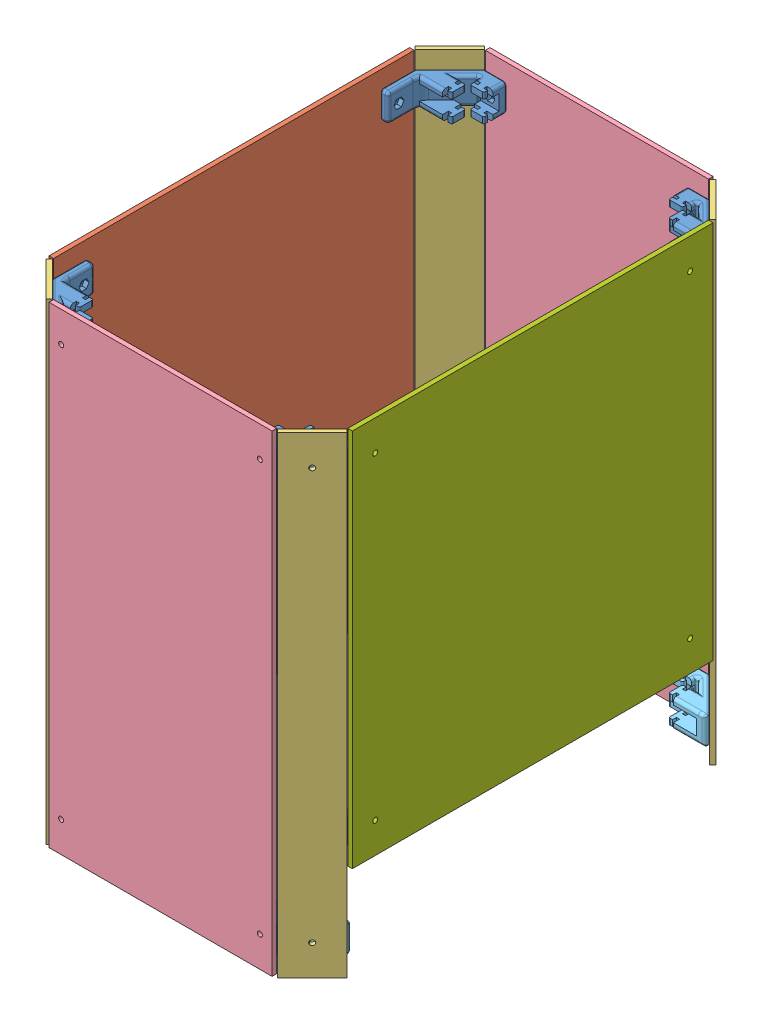
SolidWorks assembly Assemblage_plexi_exerieur, configuration Défaut. Lengths in mm.
Overall size (198.5 309 288.5).
18 component instances, 7 part files, 39 mates.
Components (placement in the parent):
- support_plexi_vis_3mm_angle_1-2: support_plexi_vis_3mm_angle_1 [Défaut] at (149.18 -29 24.6282) x (1 0 0) z (0 0 1) size (37.25 18.23 45.35)
- support_plexi_vis_3mm_angle_1-3: support_plexi_vis_3mm_angle_1 [Défaut] at (49.3175 -298 -307.1257) x (-1 0 0) z (0 0 -1) size (37.25 18.23 45.35)
- support_plexi_vis_3mm_angle_1-4: support_plexi_vis_3mm_angle_1 [Défaut] at (149.18 -11 -307.1257) x (1 0 0) z (0 0 -1) size (37.25 18.23 45.35)
- support_plexi_vis_3mm_angle_1-5: support_plexi_vis_3mm_angle_1 [Défaut] at (49.3175 -280 24.6282) x (-1 0 0) z (0 0 1) size (37.25 18.23 45.35)
- support_plexi_vis_3mm_angle_1-6: support_plexi_vis_3mm_angle_1 [Défaut] at (49.3175 -29 -307.1257) x (-1 0 0) z (0 0 -1) size (37.25 18.23 45.35)
- support_plexi_vis_3mm_angle_1-8: support_plexi_vis_3mm_angle_1 [Défaut] at (49.3175 -11 24.6282) x (-1 0 0) z (0 0 1) size (37.25 18.23 45.35)
- face arrière robot 1-1: face arrière robot 1 [Défaut] at (3 -309 -259.2487) x (0 0 1) z (-1 0 0) size (236 309 3)
- face angles-1: face angles [Défaut] at (0.9142 -309 -261.9558) x (0.707107 0 -0.707107) z (0.707107 0 0.707107) size (32 309 3)
- face angles-3: face angles [Défaut] at (23.5416 -309 2.0858) x (-0.707107 0 -0.707107) z (0.707107 0 -0.707107) size (32 309 3)
- face angles-4: face angles [Défaut] at (172.8345 -309 -0.0355) x (0.707107 0 -0.707107) z (0.707107 0 0.707107) size (32 309 3)
- face angles-5: face angles [Défaut] at (174.9558 -309 -284.5833) x (0.707107 0 0.707107) z (-0.707107 0 0.707107) size (32 309 3)
- face cotés-4: face cotés [Défaut] at (26.2487 -309 0) x (1 0 0) z (0 0 1) size (146 309 3)
- face cotés-5: face cotés [Défaut] at (26.2487 -309 -285.4975) x (1 0 0) z (0 0 1) size (146 309 3)
- support_plexi_vis_3mm_angle_2-1: support_plexi_vis_3mm_angle_2 [Défaut] at (149.18 -298 24.6282) x (1 0 0) z (0 0 1) size (37.22 18.23 25.5)
- support_plexi_vis_3mm_angle_2-2: support_plexi_vis_3mm_angle_2 [Défaut] at (149.18 -280 -307.1257) x (1 0 0) z (0 0 -1) size (37.22 18.23 25.5)
- support_plexi_vis_3mm_angle_3-1: support_plexi_vis_3mm_angle_3 [Défaut] at (149.18 -237 24.6282) x (1 0 0) z (0 0 1) size (25.25 18 31.85)
- support_plexi_vis_3mm_angle_3-2: support_plexi_vis_3mm_angle_3 [Défaut] at (149.18 -219 -307.1257) x (1 0 0) z (0 0 -1) size (25.25 18 31.85)
- face avant-3: face avant [Défaut] at (195.4975 -248 -23.2487) x (0 0 -1) z (1 0 0) size (236 248 3)
Mates (geometry in assembly coordinates):
- Coaxiale17: concentric aligned: circle of support_plexi_vis_3mm_angle-6; circle of face arrière robot 1-1
- Coaxiale18: concentric aligned: cylinder of support_plexi_vis_3mm_angle_1-3 through (40.2497 -289 -244.2487) axis (-1 0 0) radius 1.65; cylinder of face arrière robot 1-1 through (3 -289 -244.2487) axis (-1 0 0) radius 1.65
- Coaxiale19: concentric aligned: cylinder of support_plexi_vis_3mm_angle_1-5 through (40.2497 -289 -38.2487) axis (-1 0 0) radius 1.65; cylinder of face arrière robot 1-1 through (3 -289 -38.2487) axis (-1 0 0) radius 1.65
- Coaxiale20: concentric aligned: cylinder of support_plexi_vis_3mm_angle_1-8 through (40.2497 -20 -38.2487) axis (-1 0 0) radius 1.65; cylinder of face arrière robot 1-1 through (3 -20 -38.2487) axis (-1 0 0) radius 1.65
- Coïncidente71: coincident anti-aligned: plane of support_plexi_vis_3mm_angle_1-6 through (3 -29 -259.799) normal (-1 0 0); plane of face arrière robot 1-1 through (3 -309 -259.2487) normal (1 0 0)
- Coaxiale21: concentric anti-aligned: cylinder of support_plexi_vis_3mm_angle_1-6 through (44.3 -20 -241.1975) axis (-0.707107 0 -0.707107) radius 1.65; cylinder of face angles-1 through (12.2279 -20 -273.2696) axis (0.707107 0 0.707107) radius 1.65
- Coaxiale22: concentric anti-aligned: cylinder of support_plexi_vis_3mm_angle_1-3 through (44.3 -289 -241.1975) axis (-0.707107 0 -0.707107) radius 1.65; cylinder of face angles-1 through (12.2279 -289 -273.2696) axis (0.707107 0 0.707107) radius 1.65
- Coïncidente72: coincident anti-aligned: plane of support_plexi_vis_3mm_angle_1-6 through (25.6985 -29 -282.4975) normal (-0.707107 0 -0.707107); plane of face angles-1 through (3.0355 -309 -259.8345) normal (0.707107 0 0.707107)
- Coaxiale23: concentric anti-aligned: cylinder of support_plexi_vis_3mm_angle_1-8 through (44.3 -20 -41.3) axis (-0.707107 0 0.707107) radius 1.65; cylinder of face angles-3 through (12.2279 -20 -9.2279) axis (0.707107 0 -0.707107) radius 1.65
- Coaxiale24: concentric anti-aligned: cylinder of support_plexi_vis_3mm_angle_1-5 through (44.3 -289 -41.3) axis (-0.707107 0 0.707107) radius 1.65; cylinder of face angles-3 through (12.2279 -289 -9.2279) axis (0.707107 0 -0.707107) radius 1.65
- Coïncidente74: coincident anti-aligned: plane of support_plexi_vis_3mm_angle_1-8 through (25.6985 -11 0) normal (-0.707107 0 0.707107); plane of face angles-3 through (25.6629 -309 -0.0355) normal (0.707107 0 -0.707107)
- Coaxiale25: concentric aligned: cylinder of support_plexi_vis_3mm_angle_1-6 through (34.2487 -20 -282.4985) axis (0 0 1) radius 1.65; cylinder of face cotés-5 through (34.2487 -20 -285.4975) axis (0 0 1) radius 1.65
- Coaxiale26: concentric aligned: cylinder of support_plexi_vis_3mm_angle_1-3 through (34.2487 -289 -282.4985) axis (0 0 1) radius 1.65; cylinder of face cotés-5 through (34.2487 -289 -285.4975) axis (0 0 1) radius 1.65
- Coaxiale27: concentric aligned: cylinder of support_plexi_vis_3mm_angle_1-4 through (164.2487 -20 -282.4985) axis (0 0 1) radius 1.65; cylinder of face cotés-5 through (164.2487 -20 -285.4975) axis (0 0 1) radius 1.65
- Coaxiale28: concentric anti-aligned: cylinder of support_plexi_vis_3mm_angle_1-2 through (164.2487 -20 0.001) axis (0 0 -1) radius 1.65; cylinder of face cotés-4 through (164.2487 -20 0) axis (0 0 1) radius 1.65
- Coaxiale29: concentric anti-aligned: cylinder of support_plexi_vis_3mm_angle_1-8 through (34.2487 -20 0.001) axis (0 0 -1) radius 1.65; cylinder of face cotés-4 through (34.2487 -20 0) axis (0 0 1) radius 1.65
- Coaxiale30: concentric anti-aligned: cylinder of support_plexi_vis_3mm_angle_1-5 through (34.2487 -289 0.001) axis (0 0 -1) radius 1.65; cylinder of face cotés-4 through (34.2487 -289 0) axis (0 0 1) radius 1.65
- Coïncidente77: coincident anti-aligned: plane of support_plexi_vis_3mm_angle_1-8 through (40.2487 -15 0) normal (0 0 1); plane of face cotés-4 through (26.2487 -309 0) normal (0 0 -1)
- Coïncidente78: coincident anti-aligned: plane of support_plexi_vis_3mm_angle_1-6 through (40.2487 -25 -282.4975) normal (0 0 -1); plane of face cotés-5 through (26.2487 -309 -282.4975) normal (0 0 1)
- Coaxiale31: concentric anti-aligned: cylinder of face cotés-4 through (164.2487 -289 0) axis (0 0 1) radius 1.65; cylinder of support_plexi_vis_3mm_angle_2-1 through (164.2487 -289 0.001) axis (0 0 -1) radius 1.65
- Coaxiale32: concentric aligned: cylinder of face cotés-5 through (164.2487 -289 -285.4975) axis (0 0 1) radius 1.65; cylinder of support_plexi_vis_3mm_angle_2-2 through (164.2487 -289 -282.4985) axis (0 0 1) radius 1.65
- Coaxiale33: concentric anti-aligned: cylinder of face angles-5 through (186.2696 -289 -273.2695) axis (-0.707107 0 0.707107) radius 1.65; cylinder of support_plexi_vis_3mm_angle_2-2 through (154.1975 -289 -241.1975) axis (0.707107 0 -0.707107) radius 1.65
- Coaxiale34: concentric anti-aligned: cylinder of support_plexi_vis_3mm_angle_1-4 through (154.1975 -20 -241.1975) axis (0.707107 0 -0.707107) radius 1.65; cylinder of face angles-5 through (186.2696 -20 -273.2696) axis (-0.707107 0 0.707107) radius 1.65
- Coïncidente83: coincident anti-aligned: plane of support_plexi_vis_3mm_angle_1-4 through (172.799 -11 -282.4975) normal (0.707107 0 -0.707107); plane of face angles-5 through (172.8345 -309 -282.4619) normal (-0.707107 0 0.707107)
- Coaxiale35: concentric aligned: cylinder of support_plexi_vis_3mm_angle_1-2 through (154.1975 -20 -41.3) axis (0.707107 0 0.707107) radius 1.65; cylinder of face angles-4 through (184.1482 -20 -11.3492) axis (0.707107 0 0.707107) radius 1.65
- Coaxiale36: concentric aligned: cylinder of face angles-4 through (184.1482 -289 -11.3492) axis (0.707107 0 0.707107) radius 1.65; cylinder of support_plexi_vis_3mm_angle_2-1 through (154.1975 -289 -41.3) axis (0.707107 0 0.707107) radius 1.65
- Coïncidente84: coincident anti-aligned: plane of face angles-4 through (172.8345 -309 -0.0355) normal (-0.707107 0 -0.707107); plane of support_plexi_vis_3mm_angle_2-1 through (172.799 -298 0) normal (0.707107 0 0.707107)
- Coïncidente92: coincident anti-aligned: plane of support_plexi_vis_3mm_angle_1-2 through (195.4975 -29 -22.6985) normal (1 0 0); plane of face avant-3 through (195.4975 -248 -23.2487) normal (-1 0 0)
- Coaxiale45: concentric aligned: cylinder of support_plexi_vis_3mm_angle_1-2 through (158.2477 -20 -38.2487) axis (1 0 0) radius 1.65; cylinder of face avant-3 through (195.4975 -20 -38.2487) axis (1 0 0) radius 1.65
- Coaxiale46: concentric aligned: cylinder of support_plexi_vis_3mm_angle_1-4 through (158.2477 -20 -244.2487) axis (1 0 0) radius 1.65; cylinder of face avant-3 through (195.4975 -20 -244.2487) axis (1 0 0) radius 1.65
- Coaxiale47: concentric aligned: cylinder of support_plexi_vis_3mm_angle_3-1 through (158.2477 -228 -38.2487) axis (1 0 0) radius 1.65; cylinder of face avant-3 through (195.4975 -228 -38.2487) axis (1 0 0) radius 1.65
- Coaxiale48: concentric aligned: cylinder of support_plexi_vis_3mm_angle_3-2 through (158.2477 -228 -244.2487) axis (1 0 0) radius 1.65; cylinder of face avant-3 through (195.4975 -228 -244.2487) axis (1 0 0) radius 1.65
- Coïncidente96: coincident aligned: plane of support_plexi_vis_3mm_angle_3-1 through (167.7487 -219 -12.5) normal (0 1 0); plane of support_plexi_vis_3mm_angle_3-2 through (167.7487 -219 -269.9975) normal (0 1 0)
- Coïncidente97: coincident anti-aligned: plane of support_plexi_vis_3mm_angle_3-1 through (195.4975 -237 -22.6985) normal (1 0 0); plane of face avant-3 through (195.4975 -248 -23.2487) normal (-1 0 0)
- Coïncidente98: coincident anti-aligned: plane of support_plexi_vis_3mm_angle_3-2 through (195.4975 -219 -259.799) normal (1 0 0); plane of face avant-3 through (195.4975 -248 -23.2487) normal (-1 0 0)
- Coïncidente99: coincident anti-aligned: plane of support_plexi_vis_3mm_angle_1-4 through (158.2487 -15 -282.4975) normal (0 0 -1); plane of face cotés-5 through (26.2487 -309 -282.4975) normal (0 0 1)
- Coïncidente100: coincident anti-aligned: plane of support_plexi_vis_3mm_angle_1-8 through (3 -11 -22.6985) normal (-1 0 0); plane of face arrière robot 1-1 through (3 -309 -259.2487) normal (1 0 0)
- Coïncidente101: coincident anti-aligned: line of face cotés-4 through (172.2487 0 0) axis (-1 0 0)
- Coïncidente102: coincident anti-aligned: line of face arrière robot 1-1 through (0 0 -23.2487) axis (0 0 -1)
